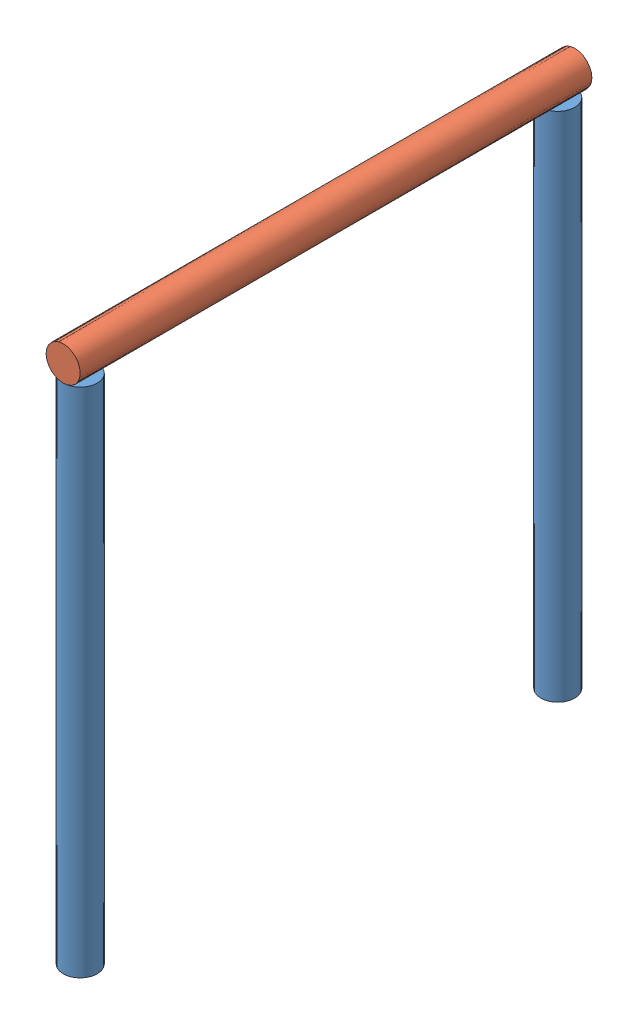
SolidWorks assembly Assem, configuration Default. Lengths in mm.
Overall size (100 1600 1500).
3 component instances, 2 part files, 6 mates.
Components (placement in the parent):
- side-1: side [Default] at origin size (100 1500 100)
- top-1: top [Default] at (0 50 -700) size (100 100 1500)
- side-2: side [Default] at (0 0 -1400) size (100 1500 100)
Mates (geometry in assembly coordinates):
- Coincident1: coincident aligned: plane of top-1 through (0 50 -700) normal (1 0 0)
- Tangent2: tangent anti-aligned: plane of side-1 through (0 0 0) normal (0 1 0); cylinder of top-1 through (0 50 50) axis (0 0 -1) radius 50
- Tangent3: tangent aligned: cylinder of side-1 through (0 -1500 0) axis (0 1 0) radius 50; plane of top-1 through (0 50 50) normal (0 0 1)
- Tangent4: tangent aligned: plane of top-1 through (0 50 -1450) normal (0 0 -1); cylinder of side-2 through (0 -1500 -1400) axis (0 1 0) radius 50
- Coincident3: coincident aligned: plane of side-2 through (0 0 -1400) normal (1 0 0)
- Tangent5: tangent anti-aligned: cylinder of top-1 through (0 50 50) axis (0 0 -1) radius 50; plane of side-2 through (0 0 -1400) normal (0 1 0)
